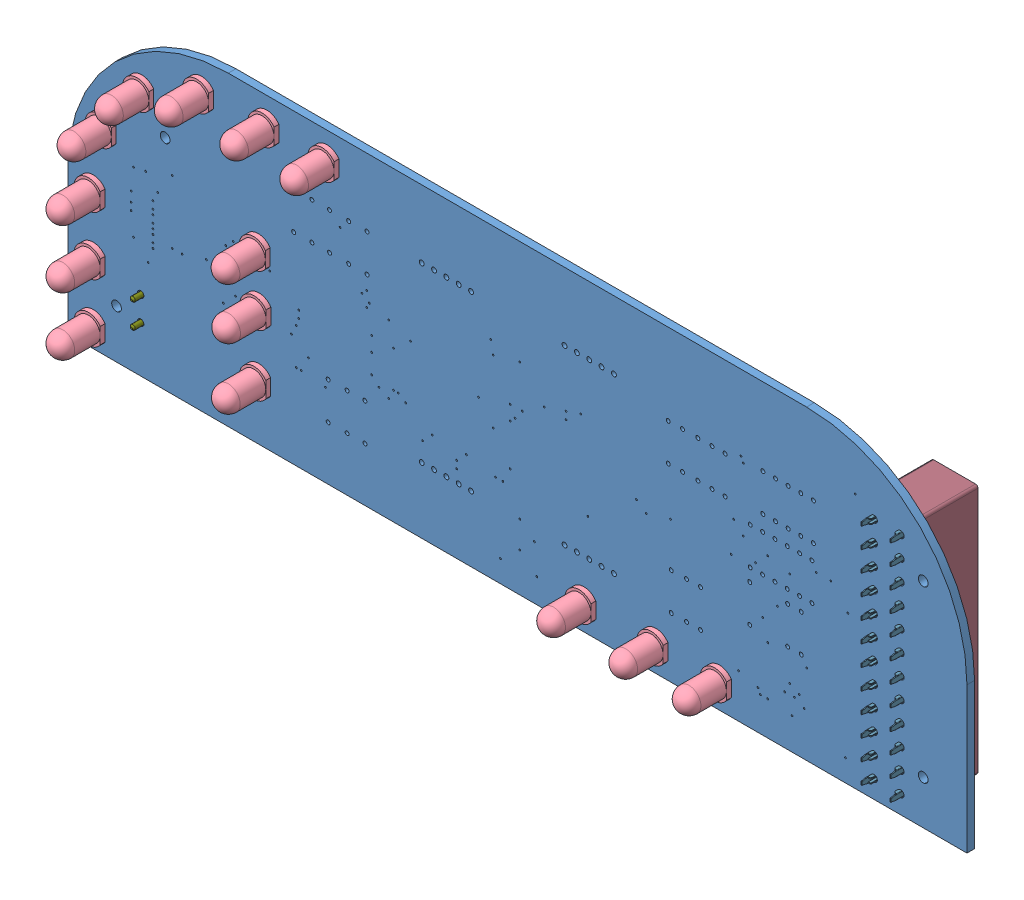
SolidWorks assembly visualizacao, configuration Valor predeterminado. Lengths in mm.
Overall size (185 64.8 27.59).
125 component instances, 18 part files, 0 mates.
Components (placement in the parent):
- PCB Component_1-1: PCB Component_1 [Valor predeterminado] at origin size (185 63 14.37)
  - Board1-1: Board1 [Valor predeterminado] at origin size (185 63 1.57)
  - 0603-1: 0603 [Valor predeterminado] at (109.344 40.367 0) x (1 0 0) z (0 0 -1) size (2.1 1.35 0.95)
  - 0603-2: 0603 [Valor predeterminado] at (94.656 28.941 0) x (-1 0 0) z (0 0 -1) size (2.1 1.35 0.95)
  - 0603-3: 0603 [Valor predeterminado] at (39.44 33.399 0) x (1 0 0) z (0 0 -1) size (2.1 1.35 0.95)
  - 0603-4: 0603 [Valor predeterminado] at (73.85 33.73 0) x (1 0 0) z (0 0 -1) size (2.1 1.35 0.95)
  - SO16-1: SO16 [Valor predeterminado] at (101.54 42.22 0) x (0 1 0) z (0 0 -1) size (10 6.2 1.75)
  - SO16-2: SO16 [Valor predeterminado] at (101.44 27.86 0) x (0 -1 0) z (0 0 -1) size (10 6.2 1.75)
  - SO16-3: SO16 [Valor predeterminado] at (31.96 33.3 0) x (0 1 0) z (0 0 -1) size (10 6.2 1.75)
  - SO16-4: SO16 [Valor predeterminado] at (66.46 33.36 0) x (0 1 0) z (0 0 -1) size (10 6.2 1.75)
  - LED5MM-1: LED5MM [Valor predeterminado] at (14.758 8.59 1.57) size (5.4 5.9 12.15)
  - LED5MM-2: LED5MM [Valor predeterminado] at (130.58 9.66 1.57) size (5.4 5.9 12.15)
  - LED5MM-3: LED5MM [Valor predeterminado] at (115.74 9.66 1.57) size (5.4 5.9 12.15)
  - LED5MM-4: LED5MM [Valor predeterminado] at (48.82 16 1.57) size (5.4 5.9 12.15)
  - LED5MM-5: LED5MM [Valor predeterminado] at (48.88 28.6 1.57) size (5.4 5.9 12.15)
  - LED5MM-6: LED5MM [Valor predeterminado] at (48.74 39.1 1.57) size (5.4 5.9 12.15)
  - LED5MM-7: LED5MM [Valor predeterminado] at (14.758 20.59 1.57) size (5.4 5.9 12.15)
  - LED5MM-8: LED5MM [Valor predeterminado] at (14.758 32.59 1.57) size (5.4 5.9 12.15)
  - LED5MM-9: LED5MM [Valor predeterminado] at (17.047 45.1 1.57) size (5.4 5.9 12.15)
  - LED5MM-10: LED5MM [Valor predeterminado] at (24.758 55.4 1.57) size (5.4 5.9 12.15)
  - LED5MM-11: LED5MM [Valor predeterminado] at (37.059 61.29 1.57) size (5.4 5.9 12.15)
  - LED5MM-12: LED5MM [Valor predeterminado] at (50.514 61.99 1.57) size (5.4 5.9 12.15)
  - LED5MM-13: LED5MM [Valor predeterminado] at (62.87 61.99 1.57) size (5.4 5.9 12.15)
  - LED5MM-14: LED5MM [Valor predeterminado] at (143.62 9.66 1.57) size (5.4 5.9 12.15)
  - SOT23-3-1: SOT23-3 [Valor predeterminado] at (73.85 26.5 0) x (1 0 0) z (0 0 -1) size (2.2 2.2 1.1)
  - SOT23-3-2: SOT23-3 [Valor predeterminado] at (109.444 48.4 0) x (1 0 0) z (0 0 -1) size (2.2 2.2 1.1)
  - SOT23-3-3: SOT23-3 [Valor predeterminado] at (94.8 34.7 0) x (-1 0 0) z (0 0 -1) size (2.2 2.2 1.1)
  - SOT23-3-4: SOT23-3 [Valor predeterminado] at (39.44 25.8 0) x (1 0 0) z (0 0 -1) size (2.2 2.2 1.1)
  - SOT23-3-5: SOT23-3 [Valor predeterminado] at (97.052 13.83 0) x (-1 0 0) z (0 0 -1) size (2.2 2.2 1.1)
  - SOT23-3-6: SOT23-3 [Valor predeterminado] at (103.743 13.83 0) x (-1 0 0) z (0 0 -1) size (2.2 2.2 1.1)
  - 0603 (1)-1: 0603 (1) [Valor predeterminado] at (109.344 37.2 0) x (-1 0 0) z (0 0 -1) size (1.75 0.95 0.55)
  - 0603 (1)-2: 0603 (1) [Valor predeterminado] at (109.344 43.534 0) x (1 0 0) z (0 0 -1) size (1.75 0.95 0.55)
  - 0603 (1)-3: 0603 (1) [Valor predeterminado] at (94.656 30.192 0) x (1 0 0) z (0 0 -1) size (1.75 0.95 0.55)
  - 0603 (1)-4: 0603 (1) [Valor predeterminado] at (94.656 25.69 0) x (1 0 0) z (0 0 -1) size (1.75 0.95 0.55)
  - 0603 (1)-5: 0603 (1) [Valor predeterminado] at (94.656 27.315 0) x (1 0 0) z (0 0 -1) size (1.75 0.95 0.55)
  - 0603 (1)-6: 0603 (1) [Valor predeterminado] at (94.656 23.566 0) x (1 0 0) z (0 0 -1) size (1.75 0.95 0.55)
  - 0603 (1)-7: 0603 (1) [Valor predeterminado] at (109.344 41.95 0) x (-1 0 0) z (0 0 -1) size (1.75 0.95 0.55)
  - 0603 (1)-8: 0603 (1) [Valor predeterminado] at (109.344 38.783 0) x (-1 0 0) z (0 0 -1) size (1.75 0.95 0.55)
  - 0603 (1)-9: 0603 (1) [Valor predeterminado] at (39.44 29.988 0) x (-1 0 0) z (0 0 -1) size (1.75 0.95 0.55)
  - 0603 (1)-10: 0603 (1) [Valor predeterminado] at (39.44 36.81 0) x (-1 0 0) z (0 0 -1) size (1.75 0.95 0.55)
  - 0603 (1)-11: 0603 (1) [Valor predeterminado] at (39.44 35.105 0) x (-1 0 0) z (0 0 -1) size (1.75 0.95 0.55)
  - 0603 (1)-12: 0603 (1) [Valor predeterminado] at (39.44 31.694 0) x (-1 0 0) z (0 0 -1) size (1.75 0.95 0.55)
  - 0603 (1)-13: 0603 (1) [Valor predeterminado] at (24.395 30.619 0) x (1 0 0) z (0 0 -1) size (1.75 0.95 0.55)
  - 0603 (1)-14: 0603 (1) [Valor predeterminado] at (24.395 28.804 0) x (1 0 0) z (0 0 -1) size (1.75 0.95 0.55)
  - 0603 (1)-15: 0603 (1) [Valor predeterminado] at (24.395 37.876 0) x (1 0 0) z (0 0 -1) size (1.75 0.95 0.55)
  - 0603 (1)-16: 0603 (1) [Valor predeterminado] at (24.395 34.247 0) x (1 0 0) z (0 0 -1) size (1.75 0.95 0.55)
  - 0603 (1)-17: 0603 (1) [Valor predeterminado] at (24.395 26.99 0) x (1 0 0) z (0 0 -1) size (1.75 0.95 0.55)
  - 0603 (1)-18: 0603 (1) [Valor predeterminado] at (24.395 39.69 0) x (1 0 0) z (0 0 -1) size (1.75 0.95 0.55)
  - 0603 (1)-19: 0603 (1) [Valor predeterminado] at (24.395 36.061 0) x (1 0 0) z (0 0 -1) size (1.75 0.95 0.55)
  - 0603 (1)-20: 0603 (1) [Valor predeterminado] at (24.395 32.433 0) x (1 0 0) z (0 0 -1) size (1.75 0.95 0.55)
  - 0603 (1)-21: 0603 (1) [Valor predeterminado] at (73.85 30.76 0) x (-1 0 0) z (0 0 -1) size (1.75 0.95 0.55)
  - 0603 (1)-22: 0603 (1) [Valor predeterminado] at (73.85 36.7 0) x (1 0 0) z (0 0 -1) size (1.75 0.95 0.55)
  - 0603 (1)-23: 0603 (1) [Valor predeterminado] at (73.85 35.215 0) x (-1 0 0) z (0 0 -1) size (1.75 0.95 0.55)
  - 0603 (1)-24: 0603 (1) [Valor predeterminado] at (73.85 32.245 0) x (-1 0 0) z (0 0 -1) size (1.75 0.95 0.55)
  - 0603 (1)-25: 0603 (1) [Valor predeterminado] at (58.71 30.268 0) x (-1 0 0) z (0 0 -1) size (1.75 0.95 0.55)
  - 0603 (1)-26: 0603 (1) [Valor predeterminado] at (58.71 28.584 0) x (-1 0 0) z (0 0 -1) size (1.75 0.95 0.55)
  - 0603 (1)-27: 0603 (1) [Valor predeterminado] at (58.71 33.636 0) x (-1 0 0) z (0 0 -1) size (1.75 0.95 0.55)
  - 0603 (1)-28: 0603 (1) [Valor predeterminado] at (58.71 26.9 0) x (-1 0 0) z (0 0 -1) size (1.75 0.95 0.55)
  - 0603 (1)-29: 0603 (1) [Valor predeterminado] at (58.71 35.32 0) x (-1 0 0) z (0 0 -1) size (1.75 0.95 0.55)
  - 0603 (1)-30: 0603 (1) [Valor predeterminado] at (58.71 31.952 0) x (-1 0 0) z (0 0 -1) size (1.75 0.95 0.55)
  - 02077-1: 02077 [Valor predeterminado] at (144.23 46.49 0) x (0 1 0) z (0 0 -1) size (8.2 1.6 3.52)
  - 02077-2: 02077 [Valor predeterminado] at (132.53 46.49 0) x (0 1 0) z (0 0 -1) size (8.2 1.6 3.52)
  - 02077-3: 02077 [Valor predeterminado] at (141.53 46.49 0) x (0 1 0) z (0 0 -1) size (8.2 1.6 3.52)
  - 02077-4: 02077 [Valor predeterminado] at (70.12 18.87 0) x (0 -1 0) z (0 0 -1) size (8.2 1.6 3.52)
  - 02077-5: 02077 [Valor predeterminado] at (66.77 49.22 0) x (0 1 0) z (0 0 -1) size (8.2 1.6 3.52)
  - 02077-6: 02077 [Valor predeterminado] at (70.55 49.22 0) x (0 1 0) z (0 0 -1) size (8.2 1.6 3.52)
  - 02077-7: 02077 [Valor predeterminado] at (62.83 49.22 0) x (0 1 0) z (0 0 -1) size (8.2 1.6 3.52)
  - 02077-8: 02077 [Valor predeterminado] at (59.21 49.22 0) x (0 1 0) z (0 0 -1) size (8.2 1.6 3.52)
  - 02077-9: 02077 [Valor predeterminado] at (55.45 49.22 0) x (0 1 0) z (0 0 -1) size (8.2 1.6 3.52)
  - 02077-10: 02077 [Valor predeterminado] at (62.55 18.87 0) x (0 -1 0) z (0 0 -1) size (8.2 1.6 3.52)
  - 02077-11: 02077 [Valor predeterminado] at (66.45 18.87 0) x (0 -1 0) z (0 0 -1) size (8.2 1.6 3.52)
  - 02077-12: 02077 [Valor predeterminado] at (138.62 46.49 0) x (0 1 0) z (0 0 -1) size (8.2 1.6 3.52)
  - 02077-13: 02077 [Valor predeterminado] at (135.47 46.49 0) x (0 1 0) z (0 0 -1) size (8.2 1.6 3.52)
  - 02077-14: 02077 [Valor predeterminado] at (133.15 20.18 0) x (0 -1 0) z (0 0 -1) size (8.2 1.6 3.52)
  - 02077-15: 02077 [Valor predeterminado] at (139.17 20.18 0) x (0 -1 0) z (0 0 -1) size (8.2 1.6 3.52)
  - 02077-16: 02077 [Valor predeterminado] at (136.29 20.18 0) x (0 -1 0) z (0 0 -1) size (8.2 1.6 3.52)
  - 02077-17: 02077 [Valor predeterminado] at (157.2 47.25 0) x (0 1 0) z (0 0 -1) size (8.2 1.6 3.52)
  - 02077-18: 02077 [Valor predeterminado] at (152 47.25 0) x (0 1 0) z (0 0 -1) size (8.2 1.6 3.52)
  - 02077-19: 02077 [Valor predeterminado] at (157.1 26.15 0) x (0 -1 0) z (0 0 -1) size (8.2 1.6 3.52)
  - 02077-20: 02077 [Valor predeterminado] at (162.4 47.25 0) x (0 1 0) z (0 0 -1) size (8.2 1.6 3.52)
  - 02077-21: 02077 [Valor predeterminado] at (159.9 26.15 0) x (0 1 0) z (0 0 -1) size (8.2 1.6 3.52)
  - 02077-22: 02077 [Valor predeterminado] at (149.3 26.15 0) x (0 1 0) z (0 0 -1) size (8.2 1.6 3.52)
  - 02077-23: 02077 [Valor predeterminado] at (154.6 47.25 0) x (0 -1 0) z (0 0 -1) size (8.2 1.6 3.52)
  - 02077-24: 02077 [Valor predeterminado] at (159.8 47.25 0) x (0 -1 0) z (0 0 -1) size (8.2 1.6 3.52)
  - 0603-RES-1: 0603-RES [Valor predeterminado] at (73.85 28.992 0) x (1 0 0) z (0 0 -1) size (1.75 0.95 0.55)
  - 0603-RES-2: 0603-RES [Valor predeterminado] at (77.7 29 0) x (-1 0 0) z (0 0 -1) size (1.75 0.95 0.55)
  - 0603-RES-3: 0603-RES [Valor predeterminado] at (108.344 51.4 0) x (1 0 0) z (0 0 -1) size (1.75 0.95 0.55)
  - 0603-RES-4: 0603-RES [Valor predeterminado] at (109.344 45.4 0) x (1 0 0) z (0 0 -1) size (1.75 0.95 0.55)
  - 0603-RES-5: 0603-RES [Valor predeterminado] at (94.656 32.1 0) x (-1 0 0) z (0 0 -1) size (1.75 0.95 0.55)
  - 0603-RES-6: 0603-RES [Valor predeterminado] at (91.3 35.7 0) x (1 0 0) z (0 0 -1) size (1.75 0.95 0.55)
  - 0603-RES-7: 0603-RES [Valor predeterminado] at (39.44 28 0) x (1 0 0) z (0 0 -1) size (1.75 0.95 0.55)
  - 0603-RES-8: 0603-RES [Valor predeterminado] at (42.9 30 0) x (-1 0 0) z (0 0 -1) size (1.75 0.95 0.55)
  - 0603-RES-9: 0603-RES [Valor predeterminado] at (97.052 10.45 0) x (-1 0 0) z (0 0 -1) size (1.75 0.95 0.55)
  - 0603-RES-10: 0603-RES [Valor predeterminado] at (97.052 17.8 0) x (0 -1 0) z (0 0 -1) size (1.75 0.95 0.55)
  - 0603-RES-11: 0603-RES [Valor predeterminado] at (103.843 10.45 0) x (-1 0 0) z (0 0 -1) size (1.75 0.95 0.55)
  - 0603-RES-12: 0603-RES [Valor predeterminado] at (103.743 17.8 0) x (0 -1 0) z (0 0 -1) size (1.75 0.95 0.55)
  - C0805K-1: C0805K [Valor predeterminado] at (148.8 8.5 0) x (-1 0 0) z (0 0 -1) size (2.1 1.35 0.95)
  - R0805-1: R0805 [Valor predeterminado] at (148 59.8 0) x (0 -1 0) z (0 0 -1) size (2.04 1.29 0.49)
  - R0805-2: R0805 [Valor predeterminado] at (144.3 59.8 0) x (0 -1 0) z (0 0 -1) size (2.04 1.29 0.49)
  - R0805-3: R0805 [Valor predeterminado] at (153.2 59.6 0) x (0 -1 0) z (0 0 -1) size (2.04 1.29 0.49)
- HT16K33-28SOP v1-1: HT16K33-28SOP v1 [Valor predeterminado] at (159.65 13.6 0) x (0 -1 0) z (0 0 -1) size (10.31 17.91 2.64)
  - Body-1: Body [Valor predeterminado] at origin size (7.06 17.91 2.44)
  - PinsArrayLR-1: PinsArrayLR [Valor predeterminado] at origin size (10.31 16.92 1.46)
- 24P I Motherboard Power connector withoout lock v2-1: 24P I Motherboard Power connector withoout lock v2 [Valor predeterminado] at (177.5 30.9 -6) x (0 -1 0) z (0 0 1) size (52 11 16.2)
  - housing 24P I withoout lock-1: housing 24P I withoout lock [Valor predeterminado] at origin size (52 11 12.8)
  - one set of pins I-1: one set of pins I [Valor predeterminado] at (42.2955 0.8635 0) size (1.1 6.2 12.6)
  - one set of pins I-2: one set of pins I [Valor predeterminado] at (38.0955 0.8635 0) size (1.1 6.2 12.6)
  - one set of pins I-3: one set of pins I [Valor predeterminado] at (33.8955 0.8635 0) size (1.1 6.2 12.6)
  - one set of pins I-4: one set of pins I [Valor predeterminado] at (29.6955 0.8635 0) size (1.1 6.2 12.6)
  - one set of pins I-5: one set of pins I [Valor predeterminado] at (25.4955 0.8635 0) size (1.1 6.2 12.6)
  - one set of pins I-6: one set of pins I [Valor predeterminado] at (21.2955 0.8635 0) size (1.1 6.2 12.6)
  - one set of pins I-7: one set of pins I [Valor predeterminado] at (17.0955 0.8635 0) size (1.1 6.2 12.6)
  - one set of pins I-8: one set of pins I [Valor predeterminado] at (12.8955 0.8635 0) size (1.1 6.2 12.6)
  - one set of pins I-9: one set of pins I [Valor predeterminado] at (8.6955 0.8635 0) size (1.1 6.2 12.6)
  - one set of pins I-10: one set of pins I [Valor predeterminado] at (4.4955 0.8635 0) size (1.1 6.2 12.6)
  - one set of pins I-11: one set of pins I [Valor predeterminado] at (0.2955 0.8635 0) size (1.1 6.2 12.6)
  - one set of pins I-12: one set of pins I [Valor predeterminado] at (-3.9045 0.8635 0) size (1.1 6.2 12.6)
- Montagem v1-1: Montagem v1 [Valor predeterminado] at (13.75 15.275 -6) x (0 -1 0) z (1 0 0) size (28.23 23.23 23.23)
  - Corpo-1: Corpo [Valor predeterminado] at (-5.9044 -4.2325 10.7) size (10.4 10.3 7.8)
  - Terminal-1: Terminal [Valor predeterminado] at (1.6956 -2.0658 10.3) size (23.23 23.23 23.23)
  - Chapa metalica-1: Chapa metalica [Valor predeterminado] at (1.6956 0.8342 10.85) x (-1 0 0) z (0 0 -1) size (4 3.5 5.4)
  - Chapa metalica-2: Chapa metalica [Valor predeterminado] at (-3.3044 0.8342 10.85) x (-1 0 0) z (0 0 -1) size (4 3.5 5.4)
  - Terminal-2: Terminal [Valor predeterminado] at (-3.3044 -2.0658 10.3) size (23.23 23.23 23.23)
  - Parafuso-1: Parafuso [Valor predeterminado] at (1.6956 3.0155 10.3) x (0.987722 0 -0.15622) z (0.15622 0 0.987722) size (14.39 14.39 14.39)
  - Parafuso-2: Parafuso [Valor predeterminado] at (-3.3044 2.8125 10.3) size (14.39 14.39 14.39)
